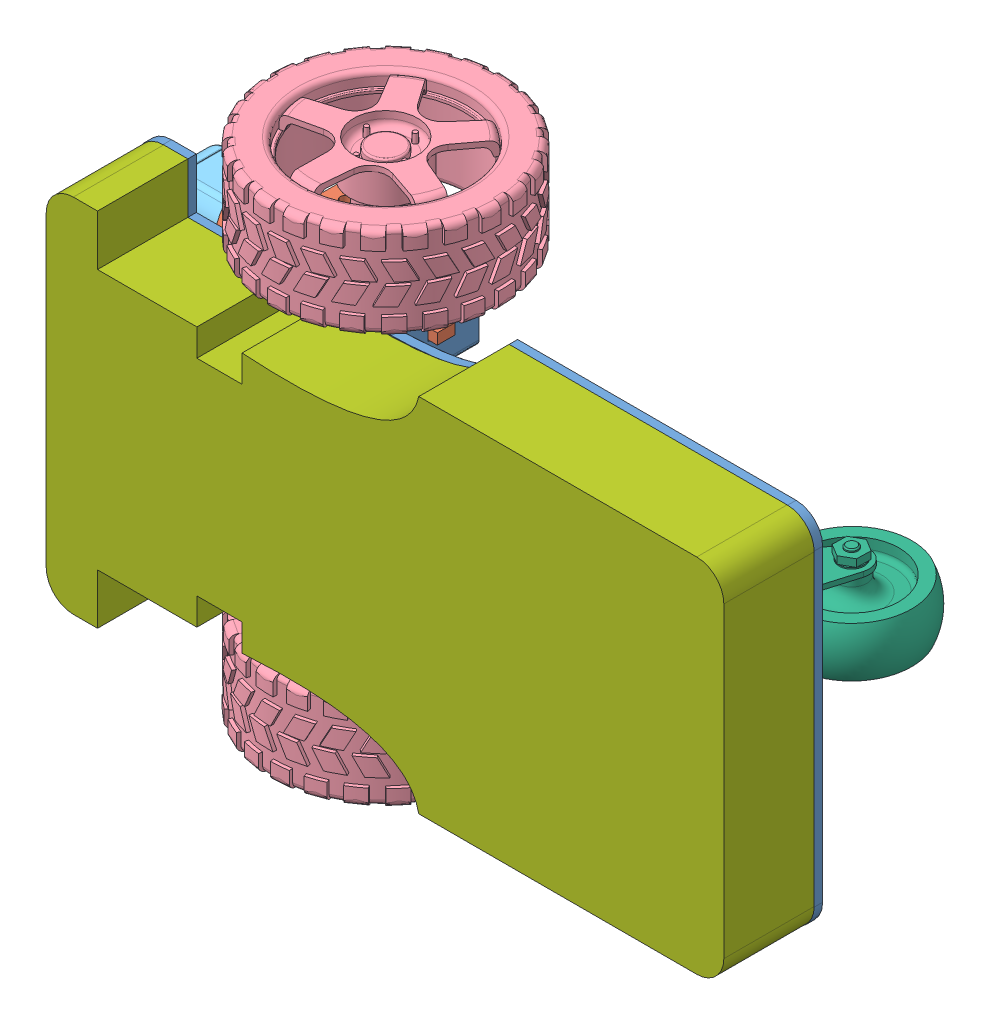
SolidWorks assembly Assem1, configuration Default. Lengths in mm.
Overall size (192.24 140.99 89.91).
13 component instances, 7 part files, 12 mates.
Components (placement in the parent):
- 1.Chassis-1: 1.Chassis [Default] at origin size (190.5 101.6 28.54)
- Real Bo Motor With Wheel-7: Real Bo Motor With Wheel [Default] at (-46.3306 -31.4531 -11.25) x (0 -1 0) z (-1 0 0) size (57.67 89.91 102.96)
  - Real Bo Motor Gear Box-1: Real Bo Motor Gear Box [Default] x (0 0 -1) z (1 0 0) size (54 22.5 18.44)
  - Shaft-1: Shaft [Default] at (0 0 -7.5) x (0 0.501874 0.864941) z (1 0 0) size (7.2 7.2 37.26)
  - Real Wheel-1: Real Wheel [Default] at (16.952 33.1259 -49.1831) x (1 0 0) z (0 -0.544629 0.838677) size (28.31 65 65)
  - Real Bo Motor Frame-2: Real Bo Motor Frame [Default] at (0 0 18.5) x (-1 0 0) z (0 1 0) size (16.44 32 20.5)
- Castor Wheel Assembly-3: Castor Wheel Assembly [Default] at (72.5515 9.5433 -24.4791) x (0 -1 0) z (-1 0 0) size (28.47 49.06 50.53)
- Real Bo Motor With Wheel-8: Real Bo Motor With Wheel [Default] at (-46.3306 31.4531 -11.25) x (0 1 0) z (-1 0 0) size (57.67 89.91 102.96)
  - Real Bo Motor Gear Box-1: Real Bo Motor Gear Box [Default] x (0 0 -1) z (1 0 0) size (54 22.5 18.44)
  - Shaft-1: Shaft [Default] at (0 0 -7.5) x (0 0.501874 0.864941) z (1 0 0) size (7.2 7.2 37.26)
  - Real Wheel-1: Real Wheel [Default] at (16.952 33.1259 -49.1831) x (1 0 0) z (0 -0.544629 0.838677) size (28.31 65 65)
  - Real Bo Motor Frame-2: Real Bo Motor Frame [Default] at (0 0 18.5) x (-1 0 0) z (0 1 0) size (16.44 32 20.5)
- 1.1.Casing-1: 1.1.Casing [Default] at (0.16 0.16 27.94) size (190.5 101.6 25.4)
Mates (geometry in assembly coordinates):
- Coincident10: coincident: plane of 1.Chassis-1 through (0 0 2.54) normal (0 0 1); plane of 1.1.Casing-1 through (-87.47 43.34 2.54) normal (0 0 -1)
- Concentric3: concentric: cylinder of 1.Chassis-1 through (87.79 43.34 0) axis (0 0 -1) radius 2.9766; cylinder of 1.1.Casing-1 through (87.79 43.34 2.54) axis (0 0 -1) radius 2.9766
- Parallel1: parallel: cylinder of 1.Chassis-1 through (-87.79 -43.34 0) axis (0 0 -1) radius 2.9766; cylinder of 1.1.Casing-1 through (-87.47 -43.02 2.54) axis (0 0 -1) radius 2.9766
- Coincident11: coincident: plane of 1.Chassis-1 through (0 0 -2.54) normal (0 0 -1); plane of Castor Wheel Assembly-3 through (51.8721 0 -2.54) normal (0 0 1)
- Concentric4: concentric: cylinder of 1.Chassis-1 through (40.6721 -11.2 -1.27) axis (0 0 -1) radius 1.397; cylinder of Castor Wheel Assembly-3 through (40.6721 -11.2 -2.54) axis (0 0 1) radius 1.4
- Concentric8: concentric: cylinder of 1.Chassis-1 through (63.0721 11.2 -1.27) axis (0 0 -1) radius 1.397; circle of Castor Wheel Assembly-3
- Coincident13: coincident: plane of 1.Chassis-1 through (-26.8306 0 -23) normal (-1 0 0); plane of Real Bo Motor With Wheel-8/Real Bo Motor Gear Box-1 through (-26.8306 40.6731 -2) normal (1 0 0)
- Coincident14: coincident: plane of 1.Chassis-1 through (0 22.2331 -23) normal (0 1 0); plane of Real Bo Motor With Wheel-8/Real Bo Motor Gear Box-1 through (-28.8306 22.2331 -20.5) normal (0 -1 0)
- Coincident15: coincident: plane of 1.Chassis-1 through (0 0 0) normal (0 0 -1); plane of Real Bo Motor With Wheel-8/Real Bo Motor Gear Box-1 through (-28.8306 40.6731 0) normal (0 0 1)
- Coincident16: coincident: plane of 1.Chassis-1 through (0 -22.2331 -23) normal (0 -1 0); plane of Real Bo Motor With Wheel-7/Real Bo Motor Gear Box-1 through (-28.8306 -22.2331 -2) normal (0 1 0)
- Coincident17: coincident: plane of 1.Chassis-1 through (0 0 0) normal (0 0 -1); plane of Real Bo Motor With Wheel-7/Real Bo Motor Gear Box-1 through (-28.8306 -40.6731 0) normal (0 0 1)
- Coincident18: coincident: plane of 1.Chassis-1 through (-26.8306 0 -23) normal (-1 0 0); plane of Real Bo Motor With Wheel-7/Real Bo Motor Gear Box-1 through (-26.8306 -40.6731 -20.5) normal (1 0 0)
